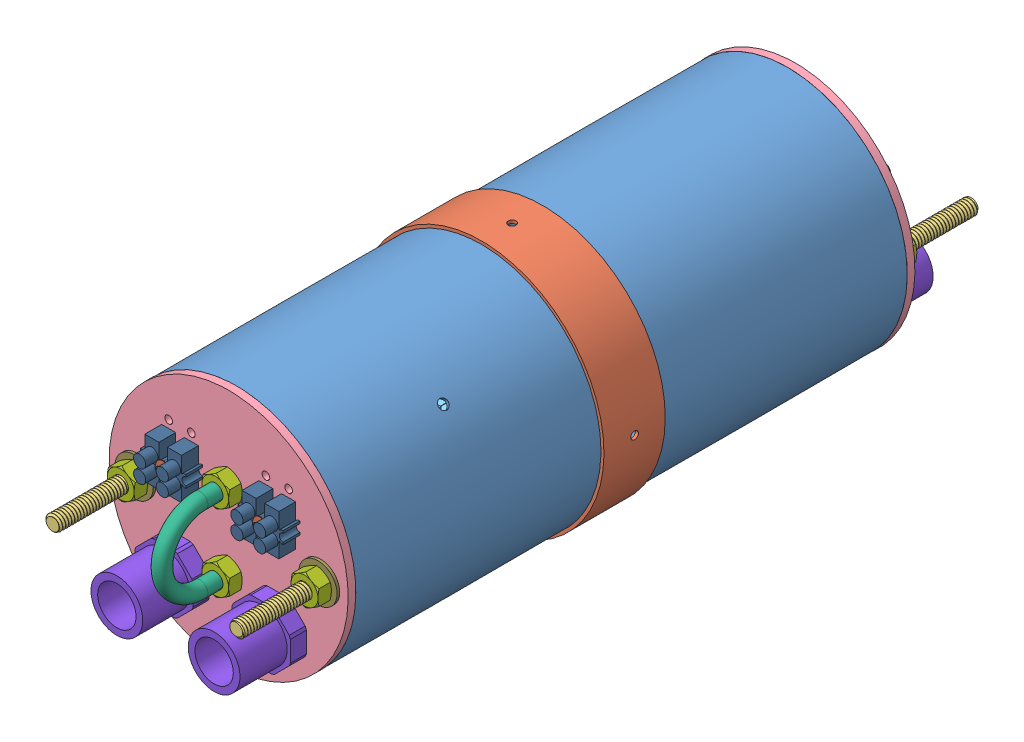
SolidWorks assembly avbay, configuration Default. Lengths in mm.
Overall size (125.39 125.39 306.5).
82 component instances, 25 part files, 39 mates.
Components (placement in the parent):
- avbay_shell-1: avbay_shell [Default] at (21.3765 -14.4764 -1.445) size (125.39 125.39 228.6)
  - avbay_coupler-1: avbay_coupler [Default] at (33.6632 130.5648 80.7782) size (99.06 99.06 228.6)
  - switchband-1: switchband [Default] at (33.6632 130.5648 207.7782) x (-0.962336 0.271862 0) z (-0.271862 -0.962336 0) size (101.6 25.4 101.6)
- threaded_rod-1: threaded_rod [90322A656] at (93.1397 116.0884 193.6332) size (7.33 6.42 306.5)
- threaded_rod-2: threaded_rod [90322A656] at (16.9397 116.0884 193.6332) x (-1 0 0) z (0 0 1) size (7.33 6.42 306.5)
- avbay_fore_bulkhead-1: avbay_fore_bulkhead [Default] at (26.7753 33.7171 358.6588) x (1 0 0) z (0 1 0) size (99.06 51.22 99.06)
  - bulkplate-1: bulkplate [Default] at (28.2644 47.5506 82.3713) size (99.06 3.17 99.06)
  - bulkplate_insert-1: bulkplate_insert [Default] at (28.2644 50.7256 82.3713) size (95.25 3.17 95.25)
  - u_bolt_fore-1: u_bolt_fore [2936T68] at (28.2644 35.7767 82.3713) x (0 0 1) z (-1 0 0) size (47.62 51.22 19.05)
  - nut-1: nut [95462A029] at (28.2644 44.7725 98.2463) x (1 0 0) z (0 -1 0) size (11.11 12.83 6.51)
  - nut-2: nut [95462A029] at (28.2644 44.7725 66.4963) x (1 0 0) z (0 1 0) size (11.11 12.83 6.51)
  - charge_cap-1: charge_cap [4880K842] at (48.4256 34.4538 57.6063) x (1 0 0) z (0 -1 0) size (24.13 24.13 26.19)
  - charge_cap-2: charge_cap [4880K842] at (8.1031 34.4538 57.6063) x (1 0 0) z (0 -1 0) size (24.13 24.13 26.19)
  - 10_32_screw-1: 10_32_screw [90600A124] at (48.4256 56.466 57.6063) x (1 0 0) z (0 1 0) size (9.17 9.17 15.64)
  - 10_32_screw-2: 10_32_screw [90600A124] at (8.1031 56.466 57.6063) x (1 0 0) z (0 1 0) size (9.17 9.17 15.64)
  - terminal_block_2-1: terminal_block_2 [Default] at (3.4041 47.5506 97.2303) x (-1 0 0) z (0 0 1) size (18.8 12.06 17.02)
  - m3_16_screw-1: m3_16_screw [92095A184] at (8.1031 38.9156 97.2303) x (1 0 0) z (0 -1 0) size (5.7 5.7 18)
  - terminal_block_2-2: terminal_block_2 [Default] at (53.1246 47.5506 97.2303) x (1 0 0) z (0 0 -1) size (18.8 12.06 17.02)
  - m3_16_screw-2: m3_16_screw [92095A184] at (48.4256 38.9156 97.2303) x (1 0 0) z (0 -1 0) size (5.7 5.7 18)
- avbay_aft_bulkhead-1: avbay_aft_bulkhead [Default] at (83.3041 33.7171 28.6075) x (-1 0 0) z (0 1 0) size (99.06 51.22 99.06)
  - bulkplate-1: bulkplate [Default] at (28.2644 47.5506 82.3713) size (99.06 3.17 99.06)
  - bulkplate_insert-1: bulkplate_insert [Default] at (28.2644 50.7256 82.3713) size (95.25 3.17 95.25)
  - u_bolt_fore-1: u_bolt_fore [2936T68] at (28.2644 35.7767 82.3713) x (0 0 1) z (-1 0 0) size (47.62 51.22 19.05)
  - nut-1: nut [95462A029] at (28.2644 44.7725 98.2463) x (1 0 0) z (0 -1 0) size (11.11 12.83 6.51)
  - nut-2: nut [95462A029] at (28.2644 44.7725 66.4963) x (1 0 0) z (0 1 0) size (11.11 12.83 6.51)
  - charge_cap-1: charge_cap [4880K842] at (48.4256 34.4538 57.6063) x (1 0 0) z (0 -1 0) size (24.13 24.13 26.19)
  - charge_cap-2: charge_cap [4880K842] at (8.1031 34.4538 57.6063) x (1 0 0) z (0 -1 0) size (24.13 24.13 26.19)
  - 10_32_screw-1: 10_32_screw [90600A124] at (48.4256 56.466 57.6063) x (1 0 0) z (0 1 0) size (9.17 9.17 15.64)
  - 10_32_screw-2: 10_32_screw [90600A124] at (8.1031 56.466 57.6063) x (1 0 0) z (0 1 0) size (9.17 9.17 15.64)
  - terminal_block_2-1: terminal_block_2 [Default] at (3.4041 47.5506 97.2303) x (-1 0 0) z (0 0 1) size (18.8 12.06 17.02)
  - m3_16_screw-1: m3_16_screw [92095A184] at (8.1031 38.9156 97.2303) x (1 0 0) z (0 -1 0) size (5.7 5.7 18)
  - terminal_block_2-2: terminal_block_2 [Default] at (53.1246 47.5506 97.2303) x (1 0 0) z (0 0 -1) size (18.8 12.06 17.02)
  - m3_16_screw-2: m3_16_screw [92095A184] at (48.4256 38.9156 97.2303) x (1 0 0) z (0 -1 0) size (5.7 5.7 18)
- nut-1: nut [95462A029] at (16.9397 116.0884 314.9785) size (11.11 12.83 6.51)
- 1_4_washer-1: 1_4_washer [90107A029] at (16.9397 116.0884 311.1082) x (1 0 0) z (0 -1 0) size (15.88 1.09 15.88)
- 1_4_washer-2: 1_4_washer [90107A029] at (16.9397 116.0884 76.1582) x (1 0 0) z (0 1 0) size (15.88 1.09 15.88)
- nut-2: nut [95462A029] at (16.9397 116.0884 72.2878) x (1 0 0) z (0 0 -1) size (11.11 12.83 6.51)
- 1_4_washer-3: 1_4_washer [90107A029] at (93.1397 116.0884 311.1082) x (1 0 0) z (0 -1 0) size (15.88 1.09 15.88)
- nut-3: nut [95462A029] at (93.1397 116.0884 72.2878) x (-1 0 0) z (0 0 -1) size (11.11 12.83 6.51)
- 1_4_washer-4: 1_4_washer [90107A029] at (93.1397 116.0884 76.1582) x (-1 0 0) z (0 -1 0) size (15.88 1.09 15.88)
- nut-4: nut [95462A029] at (93.1397 116.0884 314.9785) size (11.11 12.83 6.51)
- avbay_internals-1: avbay_internals [Default] at (103.5688 32.4647 347.1677) x (-1 0 0) z (0 0 -1) size (88.9 40.57 152.4)
  - avbay_sled-1: avbay_sled [Default] at (48.529 83.6237 42.4096) size (88.9 35.07 152.4)
  - easymini-1: easymini [Default] at (73.294 96.3237 67.0476) x (0 0 -1) z (1 0 0) size (38.1 12.14 20.32)
  - 2s-battery-1: 2s-battery [Default] at (45.9537 97.9112 116.3236) size (13.21 15.88 43.94)
  - 2s-battery-2: 2s-battery [Default] at (59.1617 97.9112 116.3236) size (13.21 15.88 43.94)
  - terminalblock-1: terminalblock [Default] at (62.626 89.9737 179.9506) (suppressed, hidden)
  - Fingertech_Switch-1: Fingertech_Switch [Default] at (81.6229 102.6936 157.1274) x (0.5 -0.866025 0) z (0.866025 0.5 0) size (19.06 6.61 12.71)
    - Mini_Power_Switch.IGS-1: Mini_Power_Switch.IGS [Default] at origin size (19.06 6.61 12.71)
      - switch half R1.1.IGS-1: switch half R1.1.IGS [Default] at (-0.0319 -2.7572 1.89) size (12.72 4.51 12.71)
      - switch half R1.1.IGS-2: switch half R1.1.IGS [Default] at (-0.0319 3.5928 1.89) x (-1 0 0) z (0 0 1) size (12.72 4.51 12.71)
      - copper tab_through hole.IGS-1: copper tab_through hole.IGS [Default] at (-4.4769 0.4178 4.3948) size (16.52 4.58 1.01)
      - copper tab.IGS-1: copper tab.IGS [Default] at (-4.4769 0.4178 -1.5988) size (16.52 4.58 1.01)
      - SHCS 4-40x375_HX-SHCS 0.112-40x0.375x0.375-S.IGS-1: SHCS 4-40x375_HX-SHCS 0.112-40x0.375x0.375-S.IGS [Default] at (-0.0319 0.4178 8.138) x (0 0 -1) z (1 0 0) size (12.09 6.61 4.66)
  - Fingertech_Switch-2: Fingertech_Switch [Default] at (81.6229 102.6936 150.7774) x (0.5 -0.866025 0) z (0.866025 0.5 0) size (19.06 6.61 12.71)
    - Mini_Power_Switch.IGS-1: Mini_Power_Switch.IGS [Default] at origin size (19.06 6.61 12.71)
      - switch half R1.1.IGS-1: switch half R1.1.IGS [Default] at (-0.0319 -2.7572 1.89) size (12.72 4.51 12.71)
      - switch half R1.1.IGS-2: switch half R1.1.IGS [Default] at (-0.0319 3.5928 1.89) x (-1 0 0) z (0 0 1) size (12.72 4.51 12.71)
      - copper tab_through hole.IGS-1: copper tab_through hole.IGS [Default] at (-4.4769 0.4178 4.3948) size (16.52 4.58 1.01)
      - copper tab.IGS-1: copper tab.IGS [Default] at (-4.4769 0.4178 -1.5988) size (16.52 4.58 1.01)
      - SHCS 4-40x375_HX-SHCS 0.112-40x0.375x0.375-S.IGS-1: SHCS 4-40x375_HX-SHCS 0.112-40x0.375x0.375-S.IGS [Default] at (-0.0319 0.4178 8.138) x (0 0 -1) z (1 0 0) size (12.09 6.61 4.66)
  - m2_25_screw-1: m2_25_screw [91292A032] at (81.3387 106.9658 155.7446) x (1 0 0) z (0 0 -1) size (3.8 3.8 27.29)
  - m2_25_screw-2: m2_25_screw [91292A032] at (85.1487 100.3666 155.7446) x (-1 0 0) z (0 0 -1) size (3.8 3.8 27.29)
  - m2_nut-1: m2_nut [90591A265] at (85.1487 100.3666 163.6246) x (1 0 0) z (0 0 -1) size (4 4.62 1.87)
  - m2_washer-1: m2_washer [93475A195] at (85.1487 100.3666 144.6446) x (-1 0 0) z (0 0 -1) size (5 5 0.4)
  - m2_washer-2: m2_washer [93475A195] at (85.1487 100.3666 162.8246) x (1 0 0) z (0 0 -1) size (5 5 0.4)
  - m2_nut-2: m2_nut [90591A265] at (81.3387 106.9658 163.6246) x (1 0 0) z (0 0 -1) size (4 4.62 1.87)
  - m2_washer-3: m2_washer [93475A195] at (81.3387 106.9658 162.8246) x (1 0 0) z (0 0 -1) size (5 5 0.4)
  - m2_washer-4: m2_washer [93475A195] at (81.3387 106.9658 144.6446) x (1 0 0) z (0 0 -1) size (5 5 0.4)
  - rrc3-2: rrc3 [Default] at (13.804 96.3237 162.2246) x (1 0 0) z (0 1 0) size (24.05 100.05 14.25)
  - m3_8_screw-9: m3_8_screw [92095A181] at (80.294 98.7611 51.3476) x (1 0 0) z (0 1 0) size (5.7 5.7 9.95)
  - m3_8_screw-10: m3_8_screw [92095A181] at (80.294 98.7611 82.7476) x (1 0 0) z (0 1 0) size (5.7 5.7 9.95)
  - m3_8_screw-11: m3_8_screw [92095A181] at (66.294 98.7611 82.7476) x (1 0 0) z (0 1 0) size (5.7 5.7 9.95)
  - m3_8_screw-12: m3_8_screw [92095A181] at (66.294 98.7611 51.3476) x (1 0 0) z (0 1 0) size (5.7 5.7 9.95)
  - m3_8_screw-13: m3_8_screw [92095A181] at (34.454 98.7611 65.8246) x (1 0 0) z (0 1 0) size (5.7 5.7 9.95)
  - m3_8_screw-14: m3_8_screw [92095A181] at (16.804 98.7611 65.8246) x (1 0 0) z (0 1 0) size (5.7 5.7 9.95)
  - m3_8_screw-15: m3_8_screw [92095A181] at (16.804 98.7611 158.9746) x (1 0 0) z (0 1 0) size (5.7 5.7 9.95)
  - m3_8_screw-16: m3_8_screw [92095A181] at (34.454 98.7611 158.9746) x (1 0 0) z (0 1 0) size (5.7 5.7 9.95)
  - m3_16_screw-1: m3_16_screw [92095A184] at (39.131 98.6087 179.9506) x (1 0 0) z (0 1 0) size (5.7 5.7 18)
  - m3_16_screw-2: m3_16_screw [92095A184] at (57.927 98.6087 179.9506) x (1 0 0) z (0 1 0) size (5.7 5.7 18)
- nut-5: nut [95462A029] at (16.9397 116.0884 149.58) x (-0.923728 -0.383049 0) z (0 0 -1) size (11.11 12.83 6.51)
- nut-7: nut [95462A029] at (93.1397 116.0884 149.58) x (-0.923728 -0.383049 0) z (0 0 -1) size (11.11 12.83 6.51)
Mates (geometry in assembly coordinates):
- Parallel1: parallel aligned: cylinder of avbay_shell-1/avbay_coupler-1 through (55.0397 116.0884 307.9332) axis (0 0 -1) radius 48.26; line of threaded_rod-1 through (93.1397 116.0884 345.5569) axis (0 0 -1)
- Parallel2: parallel aligned: cylinder of avbay_shell-1/avbay_coupler-1 through (55.0397 116.0884 307.9332) axis (0 0 -1) radius 48.26; line of threaded_rod-2 through (16.9397 116.0884 345.5569) axis (0 0 -1)
- Distance2: distance = 76.2 mm: line of threaded_rod-2 through (16.9397 116.0884 345.5569) axis (0 0 -1); line of threaded_rod-1 through (93.1397 116.0884 345.5569) axis (0 0 -1)
- Coincident6: coincident aligned: plane of threaded_rod-1 through (93.1397 116.0884 41.2332) normal (0 0 -1); plane of threaded_rod-2 through (16.9397 116.0884 41.2332) normal (0 0 -1)
- Distance3: distance = 38.1 mm aligned: plane of threaded_rod-1 through (93.1397 116.0884 41.2332) normal (0 0 -1); plane of avbay_shell-1/avbay_coupler-1 through (55.0397 116.0884 79.3332) normal (0 0 -1)
- Coincident7: coincident: plane of avbay_shell-1/avbay_coupler-1 through (55.0397 116.0884 79.3332) normal (0 1 0); line of threaded_rod-1 through (93.1397 116.0884 345.5569) axis (0 0 -1)
- Coincident8: coincident: plane of avbay_shell-1/avbay_coupler-1 through (55.0397 116.0884 79.3332) normal (0 1 0); line of threaded_rod-2 through (16.9397 116.0884 345.5569) axis (0 0 -1)
- Symmetric1: symmetric aligned: plane of avbay_shell-1/avbay_coupler-1 through (55.0397 116.0884 79.3332) normal (1 0 0); line of threaded_rod-1 through (93.1397 116.0884 345.5569) axis (0 0 -1); line of threaded_rod-2 through (16.9397 116.0884 345.5569) axis (0 0 -1)
- Parallel3: parallel anti-aligned: plane of avbay_shell-1/avbay_coupler-1 through (55.0397 116.0884 79.3332) normal (0 1 0); plane of threaded_rod-2 through (16.9397 116.0884 193.6332) normal (0 -1 0)
- Parallel4: parallel aligned: plane of avbay_shell-1/avbay_coupler-1 through (55.0397 116.0884 79.3332) normal (0 1 0); plane of threaded_rod-1 through (93.1397 116.0884 193.6332) normal (0 1 0)
- Coincident11: coincident anti-aligned: plane of avbay_shell-1/avbay_coupler-1 through (55.0397 116.0884 307.9332) normal (0 0 1); plane of avbay_fore_bulkhead-1/bulkplate-1 through (55.0397 116.0884 307.9332) normal (0 0 -1)
- Concentric1: concentric anti-aligned: cylinder of avbay_shell-1/avbay_coupler-1 through (55.0397 116.0884 307.9332) axis (0 0 -1) radius 48.26; cylinder of avbay_fore_bulkhead-1/bulkplate_insert-1 through (55.0397 116.0884 304.7582) axis (0 0 1) radius 47.625
- Concentric2: concentric aligned: cylinder of avbay_shell-1/avbay_coupler-1 through (55.0397 116.0884 307.9332) axis (0 0 -1) radius 48.26; cylinder of avbay_aft_bulkhead-1/bulkplate_insert-1 through (55.0397 116.0884 82.5082) axis (0 0 -1) radius 47.625
- Coincident12: coincident anti-aligned: plane of avbay_shell-1/avbay_coupler-1 through (55.0397 116.0884 79.3332) normal (0 0 -1); plane of avbay_aft_bulkhead-1/bulkplate-1 through (55.0397 116.0884 79.3332) normal (0 0 1)
- Parallel5: parallel aligned: plane of avbay_shell-1/avbay_coupler-1 through (55.0397 116.0884 79.3332) normal (0 1 0); plane of avbay_aft_bulkhead-1 through (83.3041 33.7171 28.6075) normal (0 1 0)
- Parallel6: parallel aligned: plane of avbay_shell-1/avbay_coupler-1 through (55.0397 116.0884 79.3332) normal (0 1 0); plane of avbay_fore_bulkhead-1 through (26.7753 33.7171 358.6588) normal (0 1 0)
- Coincident15: coincident anti-aligned: plane of washer-2 through (16.9397 116.0884 75.066) normal (0 0 -1); plane of nut-2 through (11.3835 112.8805 75.066) normal (0 0 1)
- Concentric3: concentric aligned: cylinder of washer-2 through (16.9397 116.0884 76.1582) axis (0 0 -1) radius 3.5687; circle of nut-2
- Coincident16: coincident anti-aligned: plane of nut-1 through (11.3835 119.2963 312.2004) normal (0 0 -1); plane of washer-1 through (16.9397 116.0884 312.2004) normal (0 0 1)
- Concentric4: concentric aligned: circle of nut-1; cylinder of washer-1 through (16.9397 116.0884 311.1082) axis (0 0 1) radius 3.5687
- Coincident17: coincident anti-aligned: plane of nut-3 through (98.696 119.2963 75.066) normal (0 0 1); plane of washer-4 through (93.1397 116.0884 75.066) normal (0 0 -1)
- Concentric5: concentric aligned: circle of nut-3; cylinder of washer-4 through (93.1397 116.0884 76.1582) axis (0 0 -1) radius 3.5687
- Coincident18: coincident anti-aligned: plane of washer-3 through (93.1397 116.0884 312.2004) normal (0 0 1); plane of nut-4 through (87.5835 119.2963 312.2004) normal (0 0 -1)
- Concentric6: concentric aligned: cylinder of washer-3 through (93.1397 116.0884 311.1082) axis (0 0 1) radius 3.5687; circle of nut-4
- Coincident19: coincident anti-aligned: plane of avbay_fore_bulkhead-1/bulkplate-1 through (55.0397 116.0884 311.1082) normal (0 0 1); plane of washer-1 through (16.9397 116.0884 311.1082) normal (0 0 -1)
- Concentric7: concentric anti-aligned: line of threaded_rod-2 through (16.9397 116.0884 345.5569) axis (0 0 -1); cylinder of washer-1 through (16.9397 116.0884 311.1082) axis (0 0 1) radius 3.5687
- Coincident20: coincident anti-aligned: plane of avbay_fore_bulkhead-1/bulkplate-1 through (55.0397 116.0884 311.1082) normal (0 0 1); plane of washer-3 through (93.1397 116.0884 311.1082) normal (0 0 -1)
- Concentric8: concentric anti-aligned: line of threaded_rod-1 through (93.1397 116.0884 345.5569) axis (0 0 -1); cylinder of washer-3 through (93.1397 116.0884 311.1082) axis (0 0 1) radius 3.5687
- Coincident21: coincident anti-aligned: plane of avbay_aft_bulkhead-1/bulkplate-1 through (55.0397 116.0884 76.1582) normal (0 0 -1); plane of washer-2 through (16.9397 116.0884 76.1582) normal (0 0 1)
- Coincident22: coincident anti-aligned: plane of avbay_aft_bulkhead-1/bulkplate-1 through (55.0397 116.0884 76.1582) normal (0 0 -1); plane of washer-4 through (93.1397 116.0884 76.1582) normal (0 0 1)
- Concentric9: concentric aligned: line of threaded_rod-1 through (93.1397 116.0884 345.5569) axis (0 0 -1); cylinder of washer-4 through (93.1397 116.0884 76.1582) axis (0 0 -1) radius 3.5687
- Concentric10: concentric aligned: line of threaded_rod-2 through (16.9397 116.0884 345.5569) axis (0 0 -1); cylinder of washer-2 through (16.9397 116.0884 76.1582) axis (0 0 -1) radius 3.5687
- Coincident23: coincident anti-aligned: plane of avbay_fore_bulkhead-1/bulkplate_insert-1 through (55.0397 116.0884 304.7582) normal (0 0 -1); plane of avbay_internals-1/avbay_sled-1 through (93.1397 116.0884 304.7582) normal (0 0 1)
- Concentric14: concentric anti-aligned: cylinder of avbay_fore_bulkhead-1/bulkplate_insert-1 through (16.9397 116.0884 339.5562) axis (0 0 -1) radius 3.175; cylinder of avbay_internals-1/avbay_sled-1 through (16.9397 116.0884 152.3582) axis (0 0 1) radius 3.175
- Concentric15: concentric anti-aligned: cylinder of avbay_fore_bulkhead-1/bulkplate-1 through (93.1397 116.0884 339.5562) axis (0 0 -1) radius 3.175; cylinder of avbay_internals-1/avbay_sled-1 through (93.1397 116.0884 152.3582) axis (0 0 1) radius 3.175
- Coincident27: coincident anti-aligned: plane of avbay_internals-1/avbay_sled-1 through (93.1397 116.0884 152.3582) normal (0 0 -1); plane of nut-5 through (20.8434 121.1799 152.3582) normal (0 0 1)
- Coincident28: coincident anti-aligned: plane of avbay_internals-1/avbay_sled-1 through (93.1397 116.0884 152.3582) normal (0 0 -1); plane of nut-7 through (97.0434 121.1799 152.3582) normal (0 0 1)
- Concentric16: concentric anti-aligned: circle of avbay_internals-1/avbay_sled-1; circle of nut-7
- Concentric17: concentric anti-aligned: circle of avbay_internals-1/avbay_sled-1; circle of nut-5
